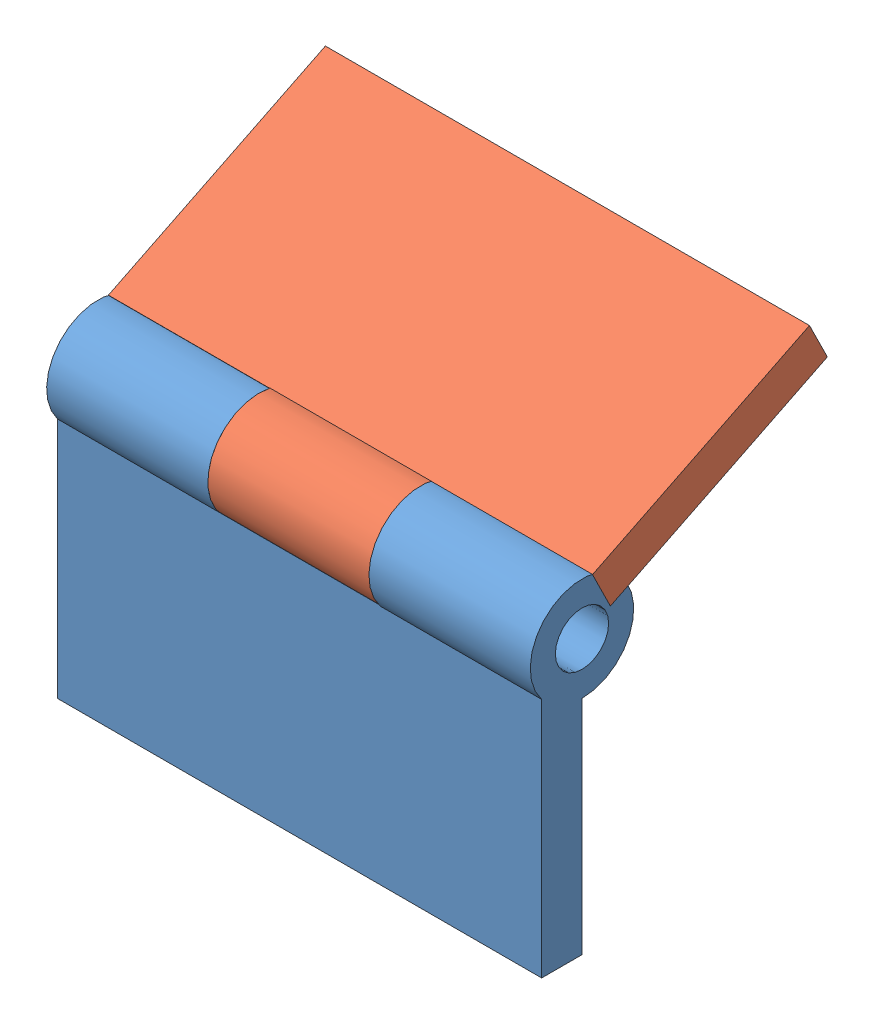
SolidWorks assembly HINGE, configuration Default. Lengths in mm.
Overall size (60 54.67 41.78).
2 component instances, 2 part files, 0 mates.
Components (placement in the parent):
- hi-1: hi [Default] at (-21.8658 30.8598 60.5669) size (60 40.34 12.83)
- hi1-1: hi1 [Default] at (38.1342 36.5235 57.049) x (-1 0 0) z (0 0.896415 0.443216) size (60 40.3 12.75)
